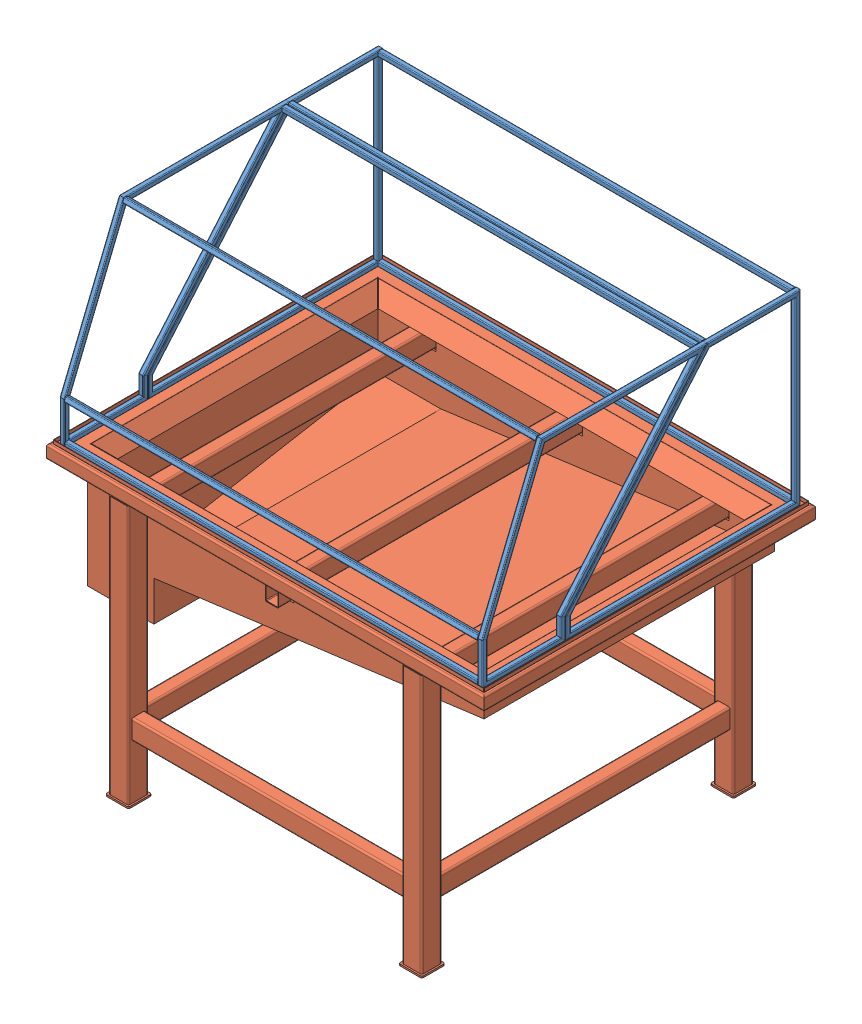
SolidWorks assembly Table and Enclosure, configuration Default. Lengths in mm.
Overall size (1676.4 1765.63 1282.7).
2 component instances, 2 part files, 4 mates.
Components (placement in the parent):
- enclosure-1: enclosure [BASE<As Machined>] at (0 9.084 3.2204) size (1619.05 717.88 1220.94)
- table-1: table [Default<As Machined>] at origin size (1676.4 1061.92 1282.7)
Mates (geometry in assembly coordinates):
- Coincident1: coordinate: point of table-1
- Coincident2: coincident anti-aligned: plane of enclosure-1 through (-793.777 25.4 283.1553) normal (0 -1 0); plane of table-1 through (-768.35 25.4 -596.9) normal (0 1 0)
- Coincident3: coincident aligned: plane of enclosure-1 through (0 9.084 3.2204) normal (1 0 0)
- Width1: width anti-aligned: plane of table-1 through (800.1 19.05 -635) normal (0 0 -1); plane of enclosure-1 through (800.1 19.05 -558.8) normal (0 0 1); plane of table-1 through (-800 28.702 -587.375) normal (0 0 1); plane of enclosure-1 through (-800 28.702 -606.425) normal (0 0 -1)
